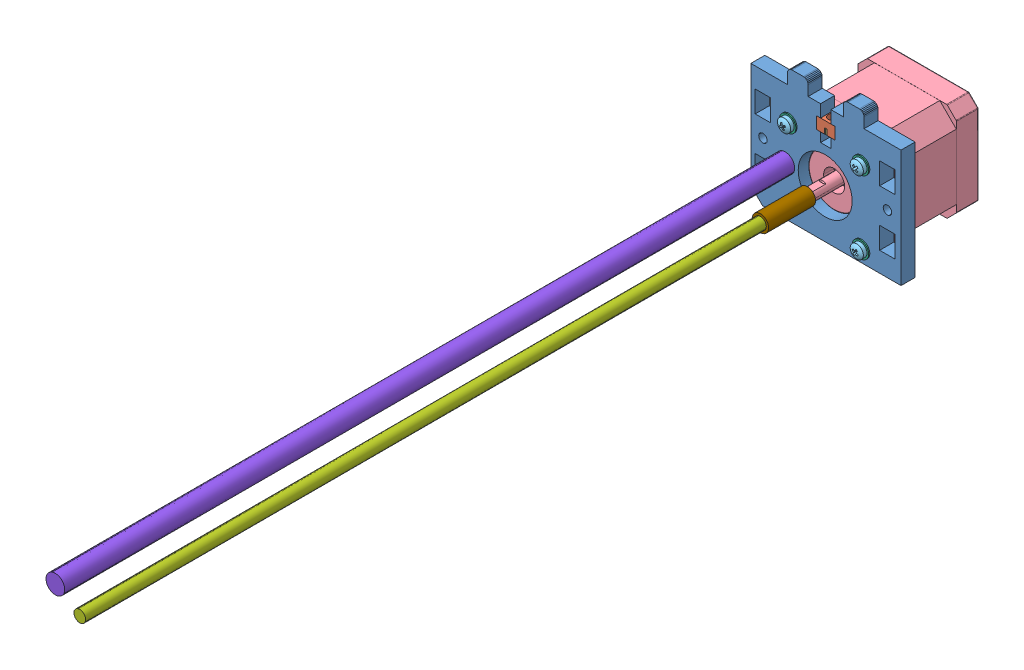
SolidWorks assembly Assembly Z-Motor Mount Bottom Left, configuration Valor predeterminado. Lengths in mm.
Overall size (64 62.65 362.01).
20 component instances, 9 part files, 23 mates.
Components (placement in the parent):
- Z-Motor Mount Bottom-1: Z-Motor Mount Bottom [Valor predeterminado] at (-65.9605 -33.419 0) size (64 56.35 6)
- Assembly m3-nut-adapter + Nut DIN 934 - M3-1: Assembly m3-nut-adapter + Nut DIN 934 - M3 [Valor predeterminado] at (0 19.7 3) x (1 0 0) z (0 -1 0) size (8.25 7.94 5.1)
  - m3-nut-adapter-1: m3-nut-adapter [Valor predeterminado] at origin size (8 6 5.1)
  - Nut DIN 934 - M3-1: Nut DIN 934 - M3 [Valor predeterminado] at (0 0 3.9) x (0 0 1) z (-0.866025 -0.5 0) size (2.4 5.5 6.35)
- Stepper motor Nema 17-1: Stepper motor Nema 17 [Valor predeterminado] at (23.9028 -0.0456 -12.5) x (0 0 -1) z (0 -1 0) size (62.01 42.01 48.01)
- Assembly Screw DIN 7985 - M3 x 10 --- 10N + Washer DIN 125A - M3-1: Assembly Screw DIN 7985 - M3 x 10 --- 10N + Washer DIN 125A - M3 [Valor predeterminado] at (23.5845 20.3733 3.1214) x (0 0 1) z (-0.691568 -0.722312 0) size (12.37 7 7)
  - Screw DIN 7985 - M3 x 10 --- 10N-1: Screw DIN 7985 - M3 x 10 --- 10N [Valor predeterminado] at (5.7786 -0.3419 12.3725) size (12.37 5.6 5.6)
  - Washer DIN 125A - M3-1: Washer DIN 125A - M3 [Valor predeterminado] at (2.8786 -0.3419 12.3725) size (0.5 7 7)
- Assembly Screw DIN 7985 - M3 x 10 --- 10N + Washer DIN 125A - M3-2: Assembly Screw DIN 7985 - M3 x 10 --- 10N + Washer DIN 125A - M3 [Valor predeterminado] at (26.3467 -25.3329 3.1214) x (0 0 1) z (-0.881833 0.471562 0) size (12.37 7 7)
  - Screw DIN 7985 - M3 x 10 --- 10N-1: Screw DIN 7985 - M3 x 10 --- 10N [Valor predeterminado] at (5.7786 -0.3419 12.3725) size (12.37 5.6 5.6)
  - Washer DIN 125A - M3-1: Washer DIN 125A - M3 [Valor predeterminado] at (2.8786 -0.3419 12.3725) size (0.5 7 7)
- Assembly Screw DIN 7985 - M3 x 10 --- 10N + Washer DIN 125A - M3-3: Assembly Screw DIN 7985 - M3 x 10 --- 10N + Washer DIN 125A - M3 [Valor predeterminado] at (-9.7752 -30.6534 3.1214) x (0 0 1) z (-0.4563 0.889826 0) size (12.37 7 7)
  - Screw DIN 7985 - M3 x 10 --- 10N-1: Screw DIN 7985 - M3 x 10 --- 10N [Valor predeterminado] at (5.7786 -0.3419 12.3725) size (12.37 5.6 5.6)
  - Washer DIN 125A - M3-1: Washer DIN 125A - M3 [Valor predeterminado] at (2.8786 -0.3419 12.3725) size (0.5 7 7)
- Assembly Screw DIN 7985 - M3 x 10 --- 10N + Washer DIN 125A - M3-4: Assembly Screw DIN 7985 - M3 x 10 --- 10N + Washer DIN 125A - M3 [Valor predeterminado] at (-9.7752 0.3466 3.1214) x (0 0 1) z (-0.4563 0.889826 0) size (12.37 7 7)
  - Screw DIN 7985 - M3 x 10 --- 10N-1: Screw DIN 7985 - M3 x 10 --- 10N [Valor predeterminado] at (5.7786 -0.3419 12.3725) size (12.37 5.6 5.6)
  - Washer DIN 125A - M3-1: Washer DIN 125A - M3 [Valor predeterminado] at (2.8786 -0.3419 12.3725) size (0.5 7 7)
- Threaded Rod DIN 975 - M5 x 300-1: Threaded Rod DIN 975 - M5 x 300 [Valor predeterminado] at (-0.225 -4.3 173.6) x (0.307754 0.951466 0) z (0 0 1) size (5 5 300)
- Smooth Rod - 8 x 317-1: Smooth Rod - 8 x 317 [Valor predeterminado] at (-17.225 -4.3 158.5) x (0.574817 -0.818282 0) z (0 0 1) size (8 8 317)
- Hose shaft coupler - 7 x 20-1: Hose shaft coupler - 7 x 20 [Valor predeterminado] at (-0.225 -4.3 23.6) x (0.528262 0.849082 0) z (0 0 1) size (7 7 20)
Mates (geometry in assembly coordinates):
- Coincidente1: coincident: plane of assembly; plane of assembly; plane of Z-Motor Mount Bottom-1 through (-65.9605 -33.419 6) normal (0 0 1); plane of Assembly m3-nut-adapter + Nut DIN 934 - M3-1/m3-nut-adapter-1 through (-4 14.6 6) normal (0 0 1)
- Coincidente2: coincident: plane of assembly; plane of assembly; plane of Z-Motor Mount Bottom-1 through (4 19.7 6) normal (-1 0 0); plane of Assembly m3-nut-adapter + Nut DIN 934 - M3-1/m3-nut-adapter-1 through (4 14.6 6) normal (1 0 0)
- Coincidente3: coincident: plane of assembly; plane of assembly; plane of Z-Motor Mount Bottom-1 through (-4 19.7 6) normal (0 -1 0); plane of Assembly m3-nut-adapter + Nut DIN 934 - M3-1/m3-nut-adapter-1 through (0 19.7 3) normal (0 1 0)
- Concêntrico1: concentric: cylinder of assembly; cylinder of assembly; cylinder of Z-Motor Mount Bottom-1 through (-0.225 -4.3 6) axis (0 0 -1) radius 11.5; cylinder of Stepper motor Nema 17-1 through (-0.225 -4.3 0.85) axis (0 0 1) radius 11
- Coincidente4: coincident: plane of assembly; plane of assembly; plane of Z-Motor Mount Bottom-1 through (-65.9605 -33.419 0) normal (0 0 -1); plane of Stepper motor Nema 17-1 through (-0.225 -4.3 0) normal (0 0 1)
- Paralelo1: parallel: plane of assembly; plane of assembly; plane of Z-Motor Mount Bottom-1 through (-26.925 -25 6) normal (0 -1 0); plane of Stepper motor Nema 17-1 through (20.775 -25.3 -7) normal (0 -1 0)
- Concêntrico2: concentric: cylinder of assembly; cylinder of assembly; cylinder of Stepper motor Nema 17-1 through (15.275 11.2 -3.5) axis (0 0 1) radius 1.5; cylinder of Assembly Screw DIN 7985 - M3 x 10 --- 10N + Washer DIN 125A - M3-1/Screw DIN 7985 - M3 x 10 --- 10N-1 through (15.275 11.2 8.9) axis (0 0 1) radius 1.5
- Coincidente6: coincident: plane of assembly; plane of assembly; plane of Z-Motor Mount Bottom-1 through (-65.9605 -33.419 6) normal (0 0 1); plane of Assembly Screw DIN 7985 - M3 x 10 --- 10N + Washer DIN 125A - M3-1/Washer DIN 125A - M3-1 through (15.275 11.2 6) normal (0 0 -1)
- Concêntrico3: concentric: cylinder of assembly; cylinder of assembly; cylinder of Stepper motor Nema 17-1 through (15.275 -19.8 -3.5) axis (0 0 1) radius 1.5; cylinder of Assembly Screw DIN 7985 - M3 x 10 --- 10N + Washer DIN 125A - M3-2/Screw DIN 7985 - M3 x 10 --- 10N-1 through (15.275 -19.8 8.9) axis (0 0 1) radius 1.5
- Coincidente7: coincident: plane of assembly; plane of assembly; plane of Z-Motor Mount Bottom-1 through (-65.9605 -33.419 6) normal (0 0 1); plane of Assembly Screw DIN 7985 - M3 x 10 --- 10N + Washer DIN 125A - M3-2/Washer DIN 125A - M3-1 through (15.275 -19.8 6) normal (0 0 -1)
- Coincidente8: coincident: plane of assembly; plane of assembly; plane of Z-Motor Mount Bottom-1 through (-65.9605 -33.419 6) normal (0 0 1); plane of Assembly Screw DIN 7985 - M3 x 10 --- 10N + Washer DIN 125A - M3-3/Washer DIN 125A - M3-1 through (-15.725 -19.8 6) normal (0 0 -1)
- Concêntrico4: concentric: cylinder of assembly; cylinder of assembly; cylinder of Stepper motor Nema 17-1 through (-15.725 -19.8 -3.5) axis (0 0 1) radius 1.5; cylinder of Assembly Screw DIN 7985 - M3 x 10 --- 10N + Washer DIN 125A - M3-3/Screw DIN 7985 - M3 x 10 --- 10N-1 through (-15.725 -19.8 8.9) axis (0 0 1) radius 1.5
- Coincidente9: coincident: plane of assembly; plane of assembly; plane of Z-Motor Mount Bottom-1 through (-65.9605 -33.419 6) normal (0 0 1); plane of Assembly Screw DIN 7985 - M3 x 10 --- 10N + Washer DIN 125A - M3-4/Washer DIN 125A - M3-1 through (-15.725 11.2 6) normal (0 0 -1)
- Concêntrico5: concentric: cylinder of assembly; cylinder of assembly; cylinder of Stepper motor Nema 17-1 through (-15.725 11.2 -3.5) axis (0 0 1) radius 1.5; cylinder of Assembly Screw DIN 7985 - M3 x 10 --- 10N + Washer DIN 125A - M3-4/Screw DIN 7985 - M3 x 10 --- 10N-1 through (-15.725 11.2 8.9) axis (0 0 1) radius 1.5
- Coincidente10: coincident: plane of assembly through (0 0 0) normal (0 0 1); plane of Z-Motor Mount Bottom-1 through (-65.9605 -33.419 0) normal (0 0 -1); plane of assembly
- Simétrico1: symmetric: plane of assembly; plane of assembly; plane of Z-Motor Mount Bottom-1 through (16.3 25 6) normal (1 0 0); plane of Z-Motor Mount Bottom-1 through (-16.3 29.35 6) normal (-1 0 0); plane of assembly
- Simétrico2: symmetric: plane of assembly; plane of assembly; plane of Z-Motor Mount Bottom-1 through (-30.045 16.5 6) normal (0 -1 0); plane of Z-Motor Mount Bottom-1 through (-23.445 -16.5 6) normal (0 1 0); plane of assembly
- Concêntrico6: concentric: cylinder of assembly; cylinder of assembly; cylinder of Stepper motor Nema 17-1 through (-0.225 -4.3 -4.4) axis (0 0 -1) radius 2.5; cylinder of Threaded Rod DIN 975 - M5 x 300-1 through (-0.225 -4.3 323.6) axis (0 0 -1) radius 2.5
- Coincidente11: coincident: plane of assembly; plane of assembly; plane of Stepper motor Nema 17-1 through (23.9028 -0.0456 23.6) normal (0 0 1); plane of Threaded Rod DIN 975 - M5 x 300-1 through (-0.225 -4.3 23.6) normal (0 0 -1)
- Concêntrico7: concentric: cylinder of assembly; cylinder of assembly; cylinder of Z-Motor Mount Bottom-1 through (-17.225 -4.3 6) axis (0 0 -1) radius 4; cylinder of Smooth Rod - 8 x 317-1 through (-17.225 -4.3 317) axis (0 0 -1) radius 4
- Coincidente12: coincident: plane of assembly; plane of assembly; plane of Stepper motor Nema 17-1 through (-0.225 -4.3 0) normal (0 0 1); plane of Smooth Rod - 8 x 317-1 through (-17.225 -4.3 0) normal (0 0 -1)
- Concêntrico8: concentric: cylinder of Threaded Rod DIN 975 - M5 x 300-1 through (-0.225 -4.3 323.6) axis (0 0 -1) radius 2.5; cylinder of ? through (-60901.8041 78582.5237 -60434.9007) axis (0 0 -1) radius 2.5
- Coincidente13: coincident: plane of assembly; plane of assembly; plane of Stepper motor Nema 17-1 through (23.9028 -0.0456 23.6) normal (0 0 1); plane of Hose shaft coupler - 7 x 20-1 through (-0.225 -4.3 23.6) normal (0 0 1)
